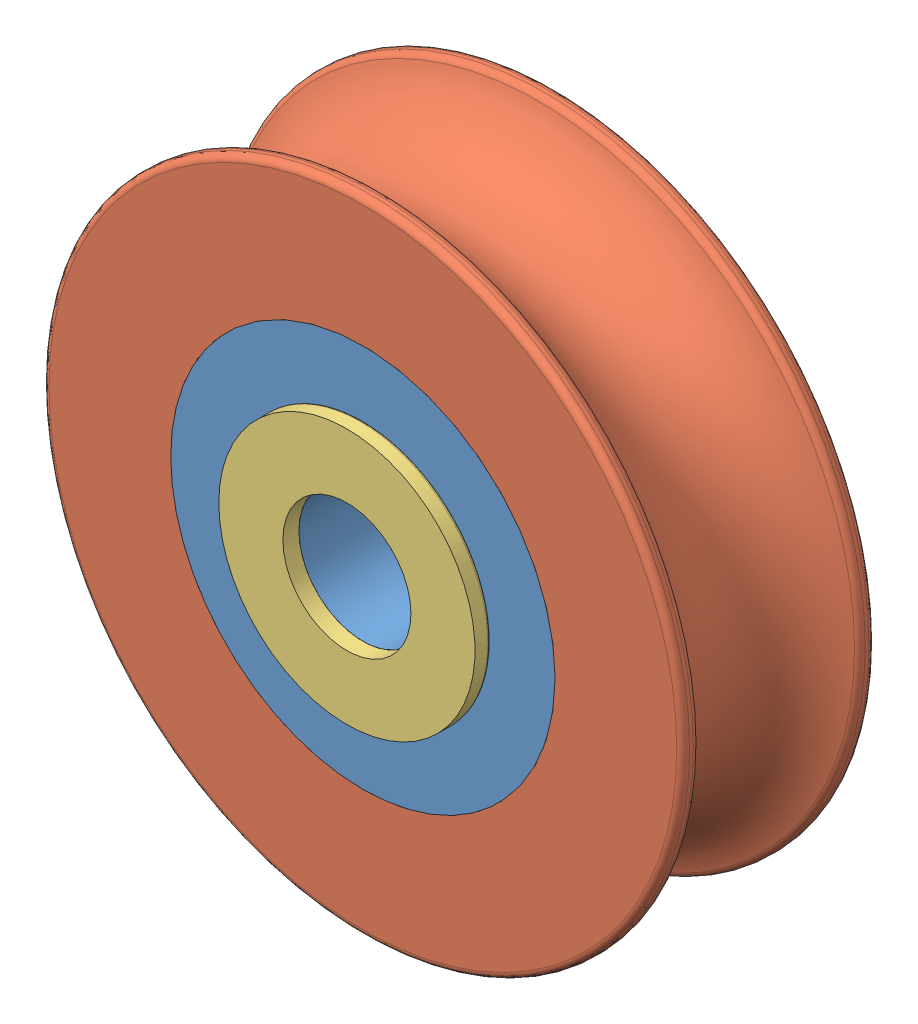
SolidWorks assembly Poulie, configuration Défaut. Lengths in mm.
Overall size (10 10 3.5).
4 component instances, 3 part files, 12 mates.
Components (placement in the parent):
- Roulement - 612-5723-1: Roulement - 612-5723 [Défaut] at origin size (6 6 3)
- Roue-2: Roue [Défaut] at origin size (10 10 3)
- Rondelle 4x2-1: Rondelle 4x2 [Défaut] at (0 0 1.5) size (4 4 0.25)
- Rondelle 4x2-2: Rondelle 4x2 [Défaut] at (0 0 -1.5) x (-0.923728 -0.383049 0) z (0 0 -1) size (4 4 0.25)
Mates (geometry in assembly coordinates):
- Coaxiale1: concentric: cylinder of Roulement - 612-5723-1 through (-1.5594 0.141 6) axis (0 0 1) radius 3; cylinder of ? through (-1.5594 0.141 7) axis (0 0 1) radius 4
- Coïncidente1: coincident aligned: plane of Roulement - 612-5723-1 through (-1.5594 3.141 4.5) normal (0 0 -1); plane of ? through (-1.5594 4.141 4.5) normal (0 0 -1)
- Coïncidente2: coincident aligned: plane of Roulement - 612-5723-1 through (0 0 0) normal (0 0 1); plane of assembly through (0 0 0) normal (0 0 1)
- Coïncidente3: coincident aligned: plane of Roulement - 612-5723-1 through (0 0 0) normal (0 1 0); plane of assembly through (0 0 0) normal (0 1 0)
- Coïncidente4: coincident aligned: plane of Roulement - 612-5723-1 through (0 0 0) normal (1 0 0); plane of assembly through (0 0 0) normal (1 0 0)
- Coïncidente5: coincident aligned: plane of Roulement - 612-5723-1 through (0 0 0) normal (0 0 1); plane of Roue-2 through (0 0 0) normal (0 0 1)
- Coïncidente6: coincident aligned: plane of Roulement - 612-5723-1 through (0 0 0) normal (0 1 0); plane of Roue-2 through (0 0 0) normal (0 1 0)
- Coïncidente7: coincident aligned: plane of Roulement - 612-5723-1 through (0 0 0) normal (1 0 0); plane of Roue-2 through (0 0 0) normal (1 0 0)
- Coïncidente8: coincident anti-aligned: plane of Roulement - 612-5723-1 through (0 3 1.5) normal (0 0 1); plane of Rondelle 4x2-1 through (0 0 1.5) normal (0 0 -1)
- Coaxiale2: concentric anti-aligned: cylinder of Roulement - 612-5723-1 through (0 0 0) axis (0 0 1) radius 1; cylinder of Rondelle 4x2-1 through (0 0 1.75) axis (0 0 -1) radius 1
- Coïncidente10: coincident anti-aligned: plane of Roulement - 612-5723-1 through (0 3 -1.5) normal (0 0 -1); plane of Rondelle 4x2-2 through (0 0 -1.5) normal (0 0 1)
- Coaxiale3: concentric aligned: cylinder of Roulement - 612-5723-1 through (0 0 0) axis (0 0 1) radius 1; cylinder of Rondelle 4x2-2 through (0 0 -1.75) axis (0 0 1) radius 1
